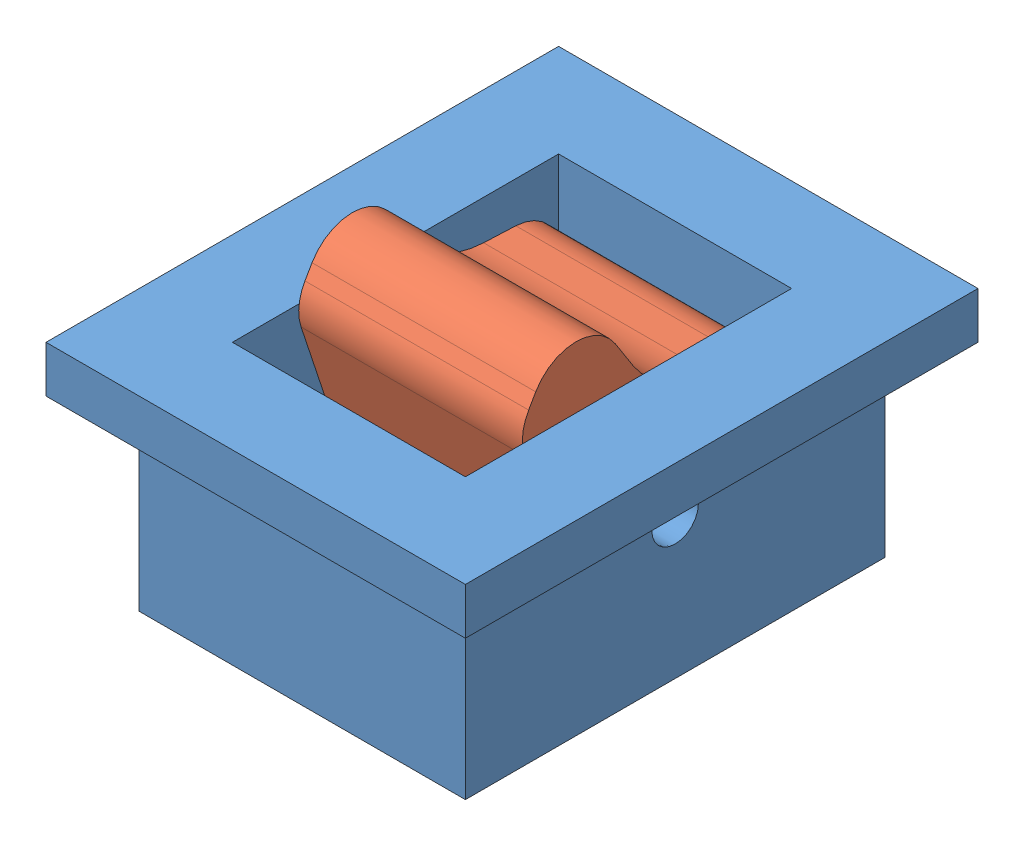
SolidWorks assembly Assem4, configuration Default. Lengths in mm.
Overall size (11.43 8.37 13.97).
3 component instances, 2 part files, 0 mates.
Components (placement in the parent):
- Assem3-1: Assem3 [Default] at origin size (11.43 8.37 13.97)
  - Switch_Housing-1: Switch_Housing [Default] at origin size (11.43 6.35 13.97)
  - Switch-1: Switch [Default] at (0 3.81 0) x (1 0 0) z (0 0.5 0.866025) size (6.1 4.97 7.62)
